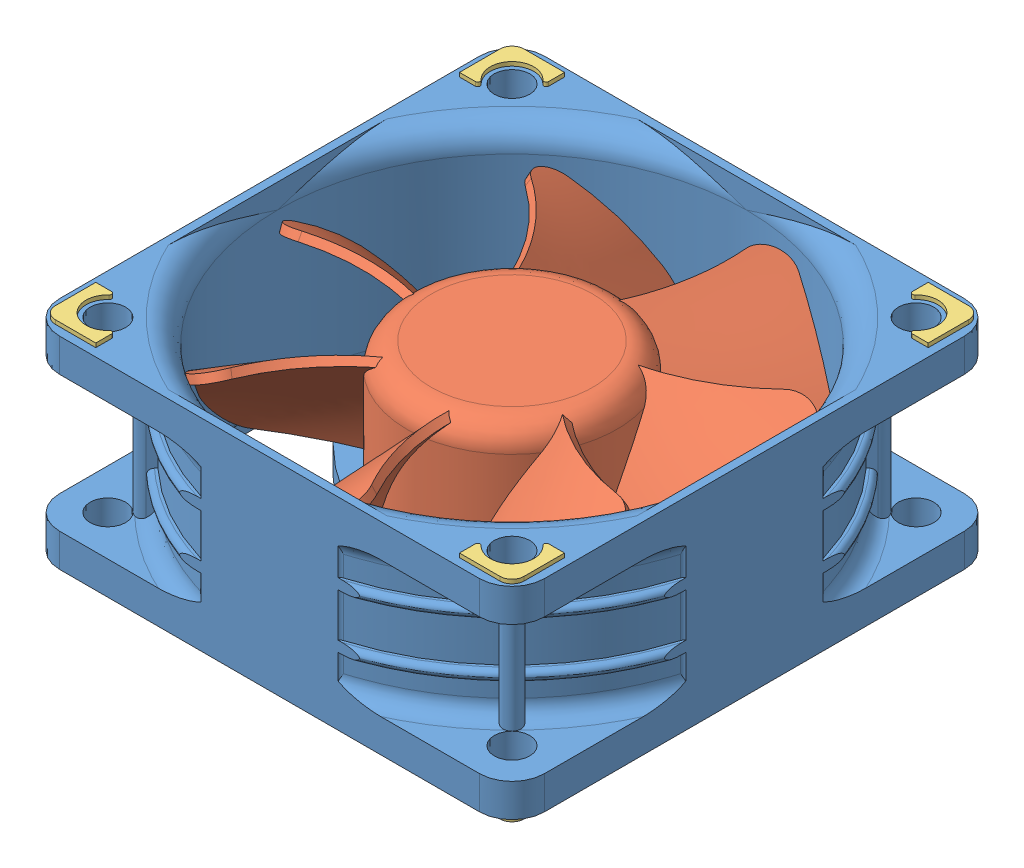
SolidWorks assembly NF A6x25, configuration NF A6x25. Lengths in mm.
Overall size (64.02 26 64.02).
3 component instances, 3 part files, 0 mates.
Components (placement in the parent):
- Component1-1: Component1 [Component1] at (0 13 0) x (1 0 0) z (0 0 -1) size (64.02 25.02 64.02)
- Component2-1: Component2 [Component2] at (0 11 0.7708) x (1 0 0) z (0 0 -1) size (59.47 16.42 59.01)
- Component3-1: Component3 [Component3] at (0 13 0) x (1 0 0) z (0 0 -1) size (58 26 58)
